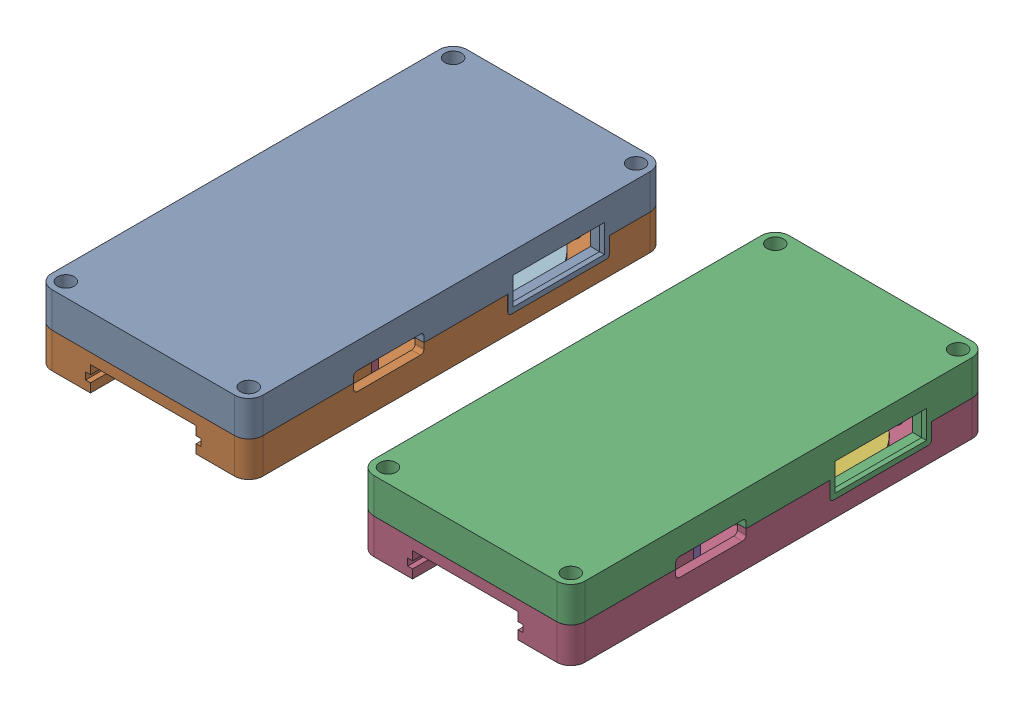
SolidWorks assembly Model V2 Assy, configuration Default. Lengths in mm.
Overall size (192.51 31.75 150.01).
14 component instances, 7 part files, 31 mates.
Components (placement in the parent):
- Back Casing-1: Back Casing [Default] at (-36.3938 11.641 11.2957) size (76.2 19.54 150.01)
- Front Casing-1: Front Casing [Default] at (-36.3938 11.6664 11.2957) size (76.2 19.05 150.01)
- Music Player Model V2-1: Music Player Model V2 [Default] at (79.9118 11.641 11.2957) size (76.2 31.75 150.01)
- PCB1_pins-1: PCB1_pins [Default] at (-36.3938 11.6664 11.2957) size (63.5 8.89 2.52)
- pin-1: pin [Default] at (-66.1034 -28.0966 11.2957) x (-0.994833 0.101523 0) z (0 0 1) size (2 2 6)
- pin-2: pin [Default] at (-50.2828 -28.0966 11.2957) x (-0.994833 0.101523 0) z (0 0 1) size (2 2 6)
- pin-3: pin [Default] at (-42.3726 -28.0966 11.2957) x (-0.994833 0.101523 0) z (0 0 1) size (2 2 6)
- pin-4: pin [Default] at (-58.1931 -28.0966 11.2957) x (-0.994833 0.101523 0) z (0 0 1) size (2 2 6)
- pin-5: pin [Default] at (-46.3277 -28.0966 11.2957) x (-0.994833 0.101523 0) z (0 0 1) size (2 2 6)
- pin-6: pin [Default] at (-54.238 -28.0966 11.2957) x (-0.994833 0.101523 0) z (0 0 1) size (2 2 6)
- pin-7: pin [Default] at (-62.1483 -28.0966 11.2957) x (-0.994833 0.101523 0) z (0 0 1) size (2 2 6)
- PCB2_interface-1: PCB2_interface [Default] at (-36.3938 11.6664 11.2957) size (70.87 1.6 77.85)
- PCB3_motherboard-1: PCB3_motherboard [Default] at (-36.3938 11.641 11.2957) size (64.33 1.6 83.51)
- pin-8: pin [Default] at (-38.4174 -28.0966 11.2957) x (-0.994833 0.101523 0) z (0 0 1) size (2 2 6)
Mates (geometry in assembly coordinates):
- Parallel1: parallel aligned: plane of Back Casing-1 through (-64.9688 -13.759 86.3019) normal (0 0 1); plane of Front Casing-1 through (-64.9688 -13.7336 86.3019) normal (0 0 1)
- Coincident2: coincident aligned: plane of Back Casing-1 through (1.7062 -13.759 11.2957) normal (1 0 0); plane of Front Casing-1 through (1.7062 -13.7336 11.2957) normal (1 0 0)
- Concentric1: concentric anti-aligned: cylinder of Back Casing-1 through (-3.3738 -1.0356 81.2219) axis (0 1 0) radius 1.6; cylinder of Front Casing-1 through (-3.3738 -1.0316 81.2219) axis (0 -1 0) radius 2.25
- Concentric2: concentric anti-aligned: cylinder of Front Casing-1 through (-8.1933 -7.3836 43.1219) axis (0 0 -1) radius 1.5875; cylinder of PCB1_pins-1 through (-8.1933 -7.3836 33.0769) axis (0 0 1) radius 1.5875
- Concentric3: concentric anti-aligned: cylinder of Front Casing-1 through (-64.5942 -7.3836 43.1219) axis (0 0 -1) radius 1.5875; cylinder of PCB1_pins-1 through (-64.5942 -7.3836 33.0769) axis (0 0 1) radius 1.5875
- Coincident3: coincident anti-aligned: plane of Front Casing-1 through (-36.3938 -7.3836 35.5969) normal (0 0 -1); plane of PCB1_pins-1 through (-36.3938 -7.3836 35.5969) normal (0 0 1)
- Concentric4: concentric anti-aligned: cylinder of PCB1_pins-1 through (-50.2368 -8.9711 33.0769) axis (0 0 1) radius 1; cylinder of pin-1 through (-50.2368 -8.9711 41.5969) axis (0 0 -1) radius 1
- Coincident4: coincident anti-aligned: plane of PCB1_pins-1 through (-36.3938 -7.3836 35.5969) normal (0 0 1); plane of pin-1 through (-64.1694 -9.145 35.5969) normal (0 0 -1)
- Concentric5: concentric aligned: cylinder of Back Casing-1 through (-7.8188 3.716 67.4805) axis (0 1 0) radius 3.175; cylinder of PCB3_motherboard-1 through (-7.8188 2.116 67.4805) axis (0 1 0) radius 0.725
- Concentric6: concentric aligned: cylinder of Back Casing-1 through (-64.9688 3.716 3.9805) axis (0 1 0) radius 3.175; cylinder of PCB3_motherboard-1 through (-64.9688 2.116 3.9805) axis (0 1 0) radius 0.725
- Coincident5: coincident anti-aligned: plane of Back Casing-1 through (-36.3938 3.716 11.2957) normal (0 -1 0); plane of PCB3_motherboard-1 through (-36.3938 3.716 42.1427) normal (0 1 0)
- Concentric7: concentric aligned: cylinder of Front Casing-1 through (-17.3438 -9.9236 22.5225) axis (0 -1 0) radius 0.725; cylinder of PCB2_interface-1 through (-17.3438 -8.3236 22.5225) axis (0 -1 0) radius 1
- Concentric8: concentric aligned: cylinder of Front Casing-1 through (-55.4438 -9.9236 -48.3435) axis (0 -1 0) radius 0.725; cylinder of PCB2_interface-1 through (-55.4438 -8.3236 -48.3435) axis (0 -1 0) radius 1
- Coincident6: coincident anti-aligned: plane of Front Casing-1 through (-36.3938 -9.9236 11.2957) normal (0 1 0); plane of PCB2_interface-1 through (-37.7273 -9.9236 -12.9105) normal (0 -1 0)
- Concentric9: concentric anti-aligned: cylinder of PCB1_pins-1 through (-46.2816 -8.9711 33.0769) axis (0 0 1) radius 1; cylinder of pin-7 through (-46.2816 -8.9711 41.5969) axis (0 0 -1) radius 1
- Concentric10: concentric anti-aligned: cylinder of PCB1_pins-1 through (-42.3265 -8.9711 33.0769) axis (0 0 1) radius 1; cylinder of pin-4 through (-42.3265 -8.9711 41.5969) axis (0 0 -1) radius 1
- Concentric11: concentric anti-aligned: cylinder of PCB1_pins-1 through (-38.3713 -8.9711 33.0769) axis (0 0 1) radius 1; cylinder of pin-6 through (-38.3713 -8.9711 41.5969) axis (0 0 -1) radius 1
- Concentric12: concentric anti-aligned: cylinder of PCB1_pins-1 through (-34.4162 -8.9711 33.0769) axis (0 0 1) radius 1; cylinder of pin-2 through (-34.4162 -8.9711 41.5969) axis (0 0 -1) radius 1
- Concentric13: concentric anti-aligned: cylinder of PCB1_pins-1 through (-30.461 -8.9711 33.0769) axis (0 0 1) radius 1; cylinder of pin-5 through (-30.461 -8.9711 41.5969) axis (0 0 -1) radius 1
- Concentric14: concentric anti-aligned: cylinder of PCB1_pins-1 through (-26.5059 -8.9711 33.0769) axis (0 0 1) radius 1; cylinder of pin-3 through (-26.5059 -8.9711 41.5969) axis (0 0 -1) radius 1
- Concentric15: concentric anti-aligned: cylinder of PCB1_pins-1 through (-22.5508 -8.9711 33.0769) axis (0 0 1) radius 1; cylinder of pin-8 through (-22.5508 -8.9711 41.5969) axis (0 0 -1) radius 1
- Coincident8: coincident aligned: plane of pin-3 through (-40.4385 -9.145 35.5969) normal (0 0 -1); plane of pin-8 through (-36.4834 -9.145 35.5969) normal (0 0 -1)
- Coincident9: coincident aligned: plane of pin-3 through (-40.4385 -9.145 35.5969) normal (0 0 -1); plane of pin-5 through (-44.3937 -9.145 35.5969) normal (0 0 -1)
- Coincident10: coincident aligned: plane of pin-2 through (-48.3488 -9.145 35.5969) normal (0 0 -1); plane of pin-5 through (-44.3937 -9.145 35.5969) normal (0 0 -1)
- Coincident11: coincident aligned: plane of pin-2 through (-48.3488 -9.145 35.5969) normal (0 0 -1); plane of pin-6 through (-52.304 -9.145 35.5969) normal (0 0 -1)
- Coincident12: coincident aligned: plane of pin-4 through (-56.2591 -9.145 35.5969) normal (0 0 -1); plane of pin-6 through (-52.304 -9.145 35.5969) normal (0 0 -1)
- Coincident13: coincident aligned: plane of pin-4 through (-56.2591 -9.145 35.5969) normal (0 0 -1); plane of pin-7 through (-60.2143 -9.145 35.5969) normal (0 0 -1)
- Coincident14: coincident aligned: plane of pin-1 through (-64.1694 -9.145 35.5969) normal (0 0 -1); plane of pin-7 through (-60.2143 -9.145 35.5969) normal (0 0 -1)
- Coincident15: coincident anti-aligned: plane of Back Casing-1 through (-36.3938 -1.0336 11.2957) normal (0 -1 0); plane of Front Casing-1 through (-36.3938 -1.0336 11.2957) normal (0 1 0)
- Coincident16: coincident aligned: plane of Back Casing-1 through (-64.9688 -13.759 86.3019) normal (0 0 1); plane of Music Player Model V2-1 through (51.3368 -13.759 86.3019) normal (0 0 1)
- Coincident17: coincident aligned: plane of Back Casing-1 through (-36.3938 11.641 11.2957) normal (0 1 0); plane of Music Player Model V2-1 through (79.9118 11.641 11.2957) normal (0 1 0)
